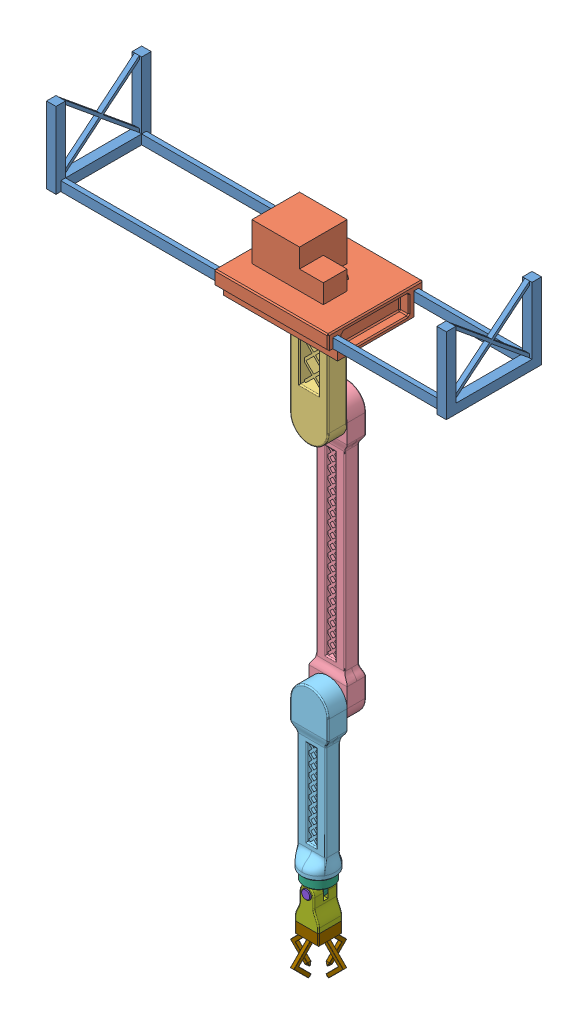
SolidWorks assembly Rafal_wrobel_assembly, configuration Domyślna. Lengths in mm.
Overall size (420 698.75 100).
9 component instances, 9 part files, 13 mates.
Components (placement in the parent):
- ramp-1: ramp [Domyślna] at (-190.4193 50.798 420) size (420 80 100)
- base-1: base [Domyślna] at (40.3711 60.798 420) size (120 75 100)
- arm1-1: arm1 [Domyślna] at (20.3711 35.798 420) size (40 120 20)
- arm2-1: arm2 [Domyślna] at (40.3711 -64.202 400) size (41.3 300 25.76)
- arm3-1: arm3 [Domyślna] at (40.3711 -324.202 420) x (-1 0 0) z (0 0 -1) size (41.14 175 35.1)
- ball_joint-1: ball_joint [Domyślna] at (40.3711 -484.202 420) x (-1 0 0) z (0 0 -1) size (30 25 30)
- arm4-1: arm4 [Domyślna] at (40.3711 -491.702 420) x (-1 0 0) z (0 0 -1) size (25.14 37.56 25.34)
- pin-1: pin [Domyślna] at (40.3711 -491.702 420) x (0.982796 -0.184696 0) z (0 0 -1) size (10 10 27)
- Gripper-1: Gripper [Domyślna] at (40.3711 -528.7792 420) x (-1 0 0) z (0 0 -1) size (55.61 46.25 55.61)
Mates (geometry in assembly coordinates):
- Coincident1: coincident aligned: line of ramp-1 through (214.5807 60.798 460) axis (-1 0 0); line of base-1 through (100.3711 60.798 460) axis (-1 0 0)
- Coincident2: coincident anti-aligned: line of base-1 through (45.3711 30.798 422.5) axis (-1 0 0); line of arm1-1 through (35.3711 30.798 422.5) axis (1 0 0)
- Coincident3: coincident anti-aligned: line of base-1 through (45.3711 30.798 417.5) axis (0 0 1); line of arm1-1 through (45.3711 30.798 422.5) axis (0 0 -1)
- Coincident4: coincident aligned: circle of arm1-1; circle of arm2-1
- Coincident5: coincident anti-aligned: circle of arm2-1; circle of arm3-1
- Coincident8: coincident anti-aligned: circle of arm3-1; circle of ball_joint-1
- Concentric1: concentric anti-aligned: cylinder of ball_joint-1 through (40.3711 -491.702 435) axis (0 0 -1) radius 3.5; cylinder of arm4-1 through (40.3711 -491.702 407.5) axis (0 0 1) radius 3.5
- Coincident9: coincident anti-aligned: plane of ball_joint-1 through (47.8711 -499.202 417.5) normal (0 0 -1); plane of arm4-1 through (40.3711 -491.702 417.5) normal (0 0 1)
- Concentric2: concentric aligned: cylinder of arm4-1 through (40.3711 -491.702 407.5) axis (0 0 1) radius 3.5; cylinder of pin-1 through (40.3711 -491.702 407.5) axis (0 0 1) radius 3.5
- Coincident10: coincident anti-aligned: plane of arm4-1 through (40.3711 -491.702 407.5) normal (0 0 -1); plane of pin-1 through (40.3711 -491.702 407.5) normal (0 0 1)
- Coincident11: coincident anti-aligned: plane of arm4-1 through (40.3711 -521.702 420) normal (0 -1 0); plane of Gripper-1 through (40.3711 -521.702 420) normal (0 1 0)
- Coincident12: coincident anti-aligned: line of arm4-1 through (51.6211 -521.702 432.5) axis (-1 0 0); line of Gripper-1 through (29.1211 -521.702 432.5) axis (1 0 0)
- Coincident13: coincident anti-aligned: line of arm4-1 through (27.8711 -521.702 431.25) axis (0 0 -1); line of Gripper-1 through (27.8711 -521.702 408.75) axis (0 0 1)
